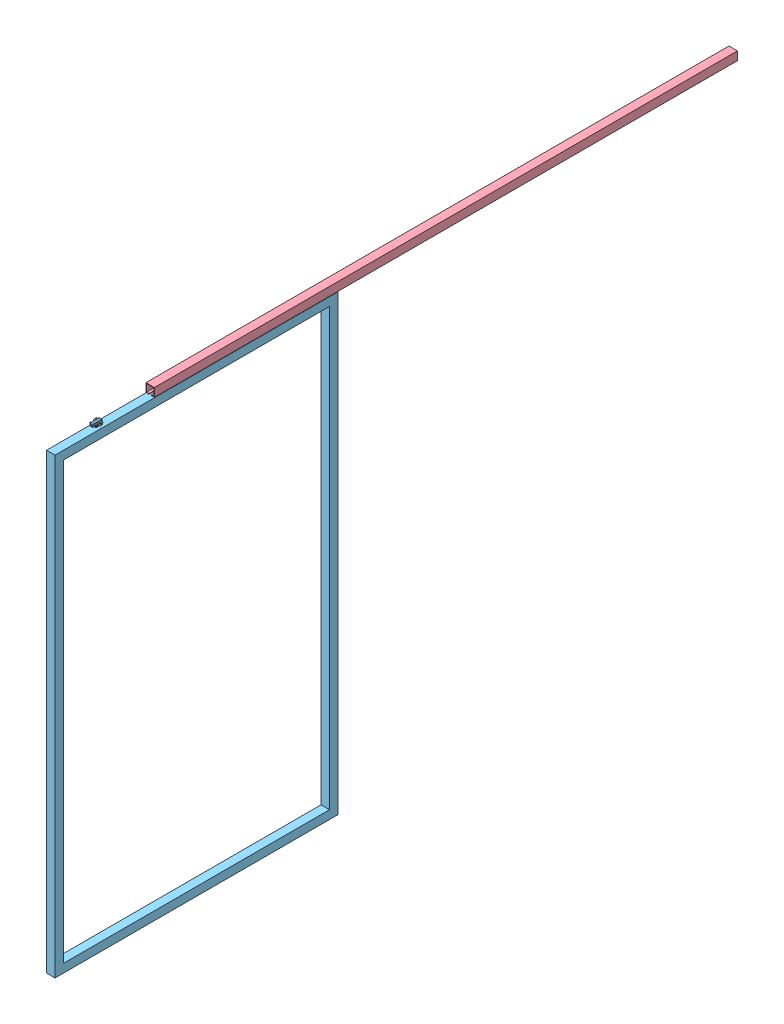
SolidWorks assembly FullDoorWithBar, configuration Default. Lengths in mm.
Overall size (30 1631.25 2411.15).
12 component instances, 5 part files, 13 mates.
Components (placement in the parent):
- FullCar-1: FullCar [Default] at (0 -5.75 1221.8966) size (25 20.7 35.41)
  - Carriage-1: Carriage [Default] at origin size (24.16 15.5 35)
  - LockWheels-1: LockWheels [Default] at (12.5 0 7.5) x (0 0.86398 0.503526) z (0 -0.503526 0.86398) size (3.5 7.63 3.5)
  - LockWheels-2: LockWheels [Default] at (12.5 0 -7.5) x (0 -0.86398 0.503526) z (0 -0.503526 -0.86398) size (3.5 7.63 3.5)
  - LockWheels-3: LockWheels [Default] at (-12.5 0 7.5) x (0 -0.86398 -0.503526) z (0 -0.503526 0.86398) size (3.5 7.63 3.5)
  - LockWheels-4: LockWheels [Default] at (-12.5 0 -7.5) x (0 0.86398 -0.503526) z (0 -0.503526 -0.86398) size (3.5 7.63 3.5)
  - WheelCarriage-1: WheelCarriage [Default] at (8 0 7.5) x (0 -0.634071 0.773275) z (1 0 0) size (14.5 14.5 3.5) (hidden)
  - WheelCarriage-2: WheelCarriage [Default] at (8 0 -7.5) x (0 -0.634071 -0.773275) z (-1 0 0) size (14.5 14.5 3.5)
  - WheelCarriage-3: WheelCarriage [Default] at (-8 0 7.5) x (0 -0.634071 0.773275) z (1 0 0) size (14.5 14.5 3.5) (hidden)
  - WheelCarriage-4: WheelCarriage [Default] at (-8 0 -7.5) x (0 -0.634071 -0.773275) z (-1 0 0) size (14.5 14.5 3.5)
- FrontHorizontalBar-1: FrontHorizontalBar [Default] at origin size (30 30 2060)
- Door-1: Door [Default] at (0 -816.25 881.1466) x (0 0 1) z (-1 0 0) size (1000 1605 30)
Mates (geometry in assembly coordinates):
- Coincident1: coincident aligned: plane of FrontHorizontalBar-1 through (0 0 0) normal (0 0 1)
- Coincident2: coincident aligned: plane of FrontHorizontalBar-1 through (0 0 0) normal (1 0 0)
- Coincident3: coincident aligned: plane of FrontHorizontalBar-1 through (0 0 0) normal (0 1 0)
- Coincident4: coincident aligned: plane of FullCar-1 through (0 -5.75 1221.8966) normal (1 0 0)
- Tangent1: tangent anti-aligned: cylinder of FullCar-1/WheelCarriage-3 through (-6.25 -5.75 1229.3966) axis (-1 0 0) radius 7.25; plane of FrontHorizontalBar-1 through (-13 -13 1030) normal (0 1 0)
- Tangent2: tangent anti-aligned: cylinder of FullCar-1/WheelCarriage-1 through (9.75 -5.75 1229.3966) axis (-1 0 0) radius 7.25; plane of FrontHorizontalBar-1 through (4 -13 1030) normal (0 1 0)
- Tangent3: tangent anti-aligned: cylinder of FullCar-1/WheelCarriage-4 through (-9.75 -5.75 1214.3966) axis (1 0 0) radius 7.25; plane of FrontHorizontalBar-1 through (-13 -13 1030) normal (0 1 0)
- Tangent4: tangent anti-aligned: cylinder of FullCar-1/WheelCarriage-2 through (6.25 -5.75 1214.3966) axis (1 0 0) radius 7.25; plane of FrontHorizontalBar-1 through (4 -13 1030) normal (0 1 0)
- Coincident5: coincident anti-aligned: plane of Door-1 through (0 -816.25 881.1466) normal (-1 0 0)
- Coincident6: coincident anti-aligned: plane of FullCar-1/Carriage-1 through (0 -11.25 1221.8966) normal (0 -1 0); plane of Door-1 through (0 -11.25 1226.1466) normal (0 1 0)
- Tangent5: tangent: plane of FullCar-1/Carriage-1 through (-3.5 -15 1216.1466) normal (0 0 1); circle of Door-1
- Coincident7: coincident anti-aligned: plane of FullCar-1/Carriage-1 through (0 -11.25 1221.8966) normal (0 -1 0); plane of Door-1 through (0 -11.25 1226.1466) normal (0 1 0)
- Coincident8: coincident: plane of FullCar-1/Carriage-1 through (-3.5 -15 1216.1466) normal (0 0 1); point of Door-1
